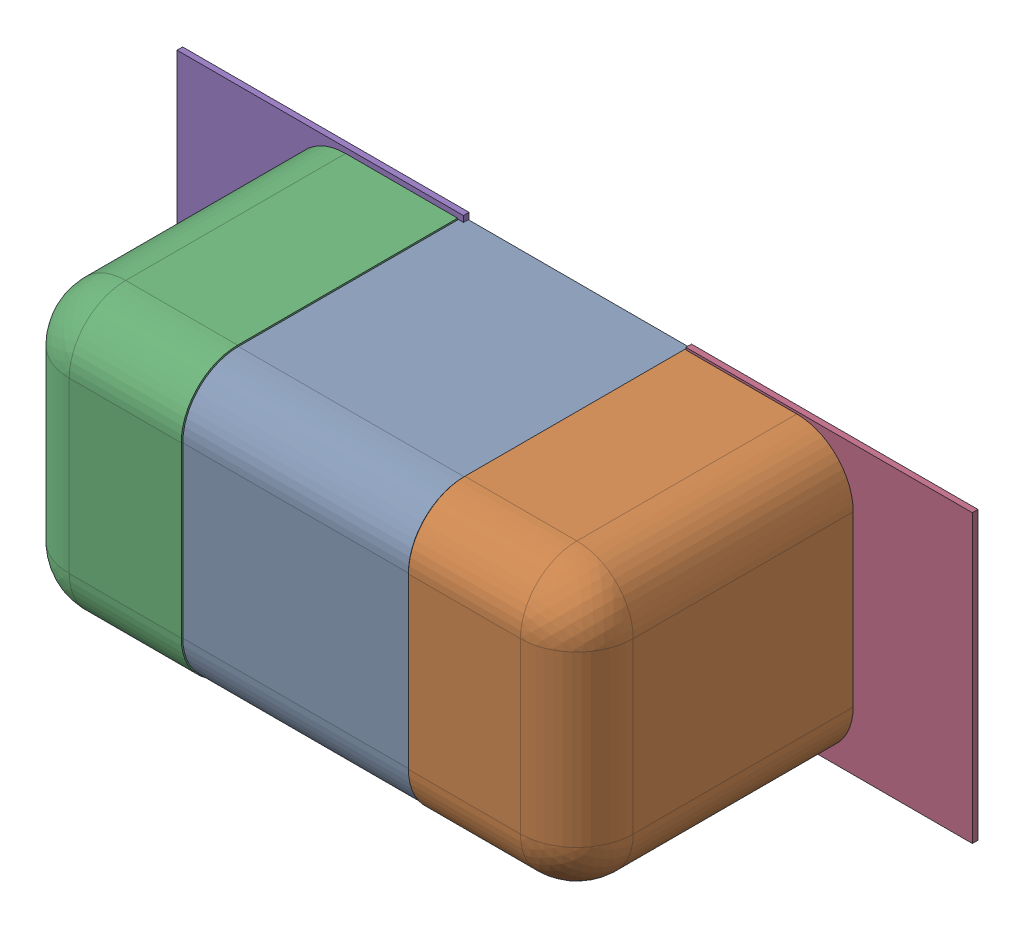
SolidWorks assembly C141, configuration Défaut. Lengths in mm.
Overall size (1.41 0.51 0.5).
8 component instances, 4 part files, 0 mates.
Components (placement in the parent):
- 6324936672-1: 6324936672 [Défaut] at (15.806 -22.2504 0) x (-1 0 0) z (0 1 0) size (1 0.5 0.5)
  - Open CASCADE STEP translator 7.5 2.131.1.1-1: Open CASCADE STEP translator 7.5 2.131.1.1 [Défaut] at origin size (0.4 0.5 0.5)
  - Open CASCADE STEP translator 7.5 2.131.1.2-1: Open CASCADE STEP translator 7.5 2.131.1.2 [Défaut] at origin size (0.3 0.5 0.5)
  - Open CASCADE STEP translator 7.5 2.131.1.3-1: Open CASCADE STEP translator 7.5 2.131.1.3 [Défaut] at origin size (0.3 0.5 0.5)
- 6504207776-1: 6504207776 [Défaut] at (16.2633 -22.2504 0) size (0.51 0.51 0.01)
  - Extruded-1: Extruded [Défaut] at origin size (0.51 0.51 0.01)
- 6504207776-2: 6504207776 [Défaut] at (15.361 -22.2452 0) size (0.51 0.51 0.01)
  - Extruded-1: Extruded [Défaut] at origin size (0.51 0.51 0.01)
